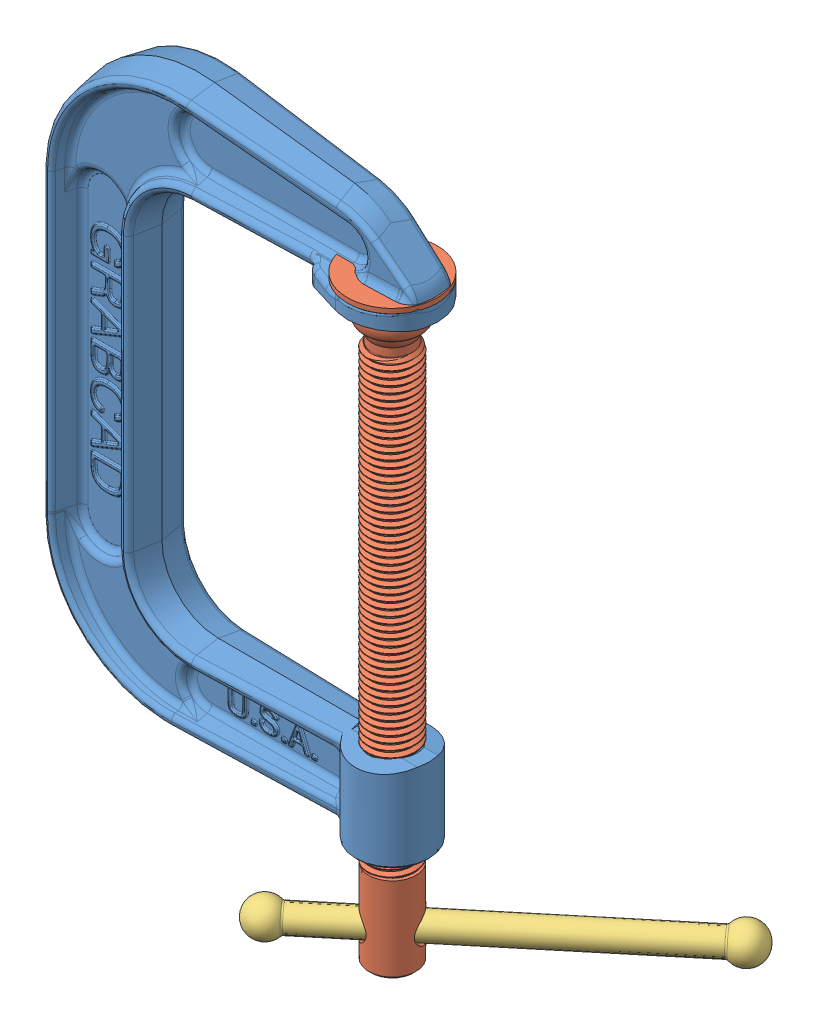
SolidWorks assembly C-Clamp, 3in, configuration Default. Lengths in mm.
Overall size (107.47 133.12 53.99).
3 component instances, 3 part files, 2 mates.
Components (placement in the parent):
- C-Clamp body-1: C-Clamp body [Default] at origin size (72.92 112.8 17.78)
- Screw-1: Screw [Default] at (22.7012 -14.642 0) x (-0.638427 0 -0.769682) z (-0.769682 0 0.638427) size (17.71 117.59 17.71)
- Screw, Lever-1: Screw, Lever [Default] at (49.7698 -15.3205 -11.261) x (0.630552 -0.156584 0.760188) z (0.769682 0 -0.638427) size (7.3 7.3 74.5)
Mates (geometry in assembly coordinates):
- Concentric1: concentric aligned: cylinder of C-Clamp body-1 through (22.7012 54.61 0) axis (0 -1 0) radius 7.2627; cylinder of Screw-1 through (22.7012 -77.4089 0) axis (0 -1 0) radius 4.6612
- Concentric2: concentric anti-aligned: cylinder of Screw-1 through (27.5887 -69.6533 -4.054) axis (-0.769682 0 0.638427) radius 2.794; cylinder of Screw, Lever-1 through (44.2704 -69.6533 -17.891) axis (0.769682 0 -0.638427) radius 2.4892
